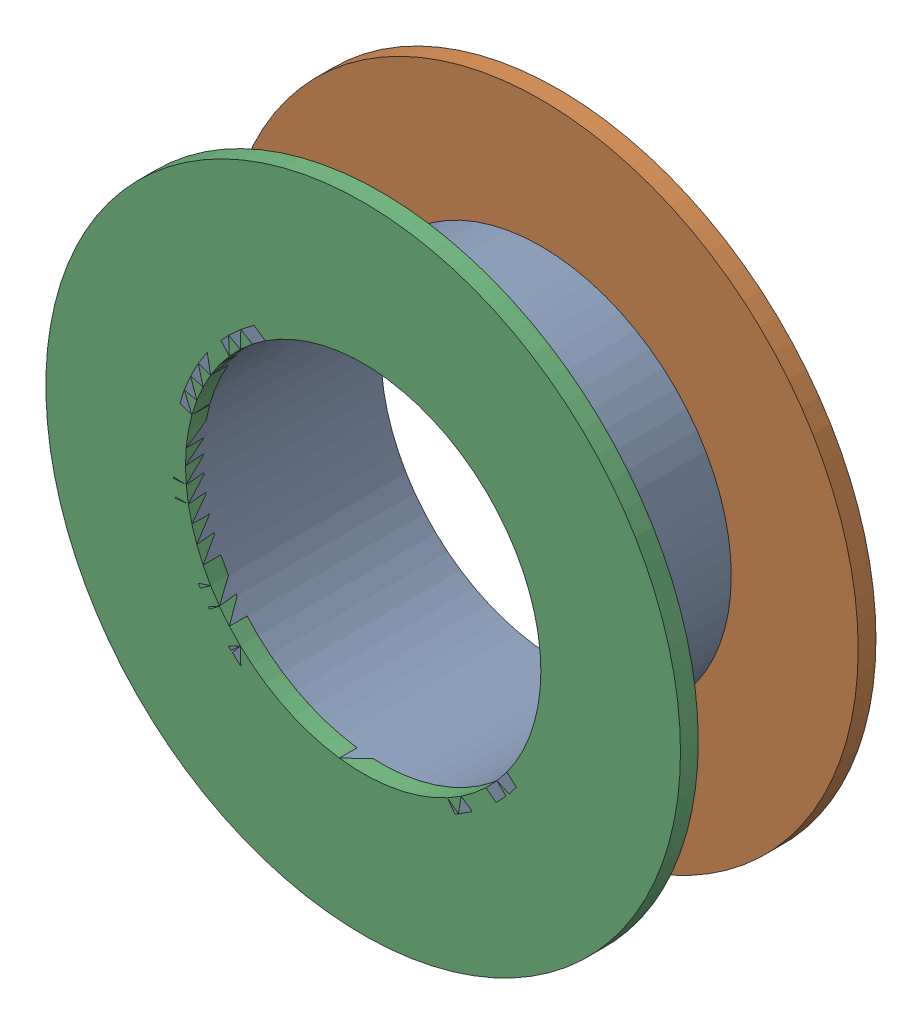
SolidWorks assembly Via (26.2mm,11mm) from Top Layer to Bottom Layer, configuration Predeterminado. Lengths in mm.
Overall size (1.27 1.27 0.39).
6 component instances, 2 part files, 0 mates.
Components (placement in the parent):
- Via Hole-1: Via Hole [Predeterminado] at (26.2 11 -0.4013) size (0.76 0.76 0.39)
  - Via Hole-Part-1-1: Via Hole-Part-1 [Predeterminado] at origin size (0.76 0.76 0.39)
- Via Top Layer-1: Via Top Layer [Predeterminado] at (26.2 11 -0.4013) size (1.27 1.27 0.04)
  - Via Top Layer-Part-1-1: Via Top Layer-Part-1 [Predeterminado] at origin size (1.27 1.27 0.04)
- Via Top Layer-2: Via Top Layer [Predeterminado] at (26.2 11 -0.0457) size (1.27 1.27 0.04)
  - Via Top Layer-Part-1-1: Via Top Layer-Part-1 [Predeterminado] at origin size (1.27 1.27 0.04)
